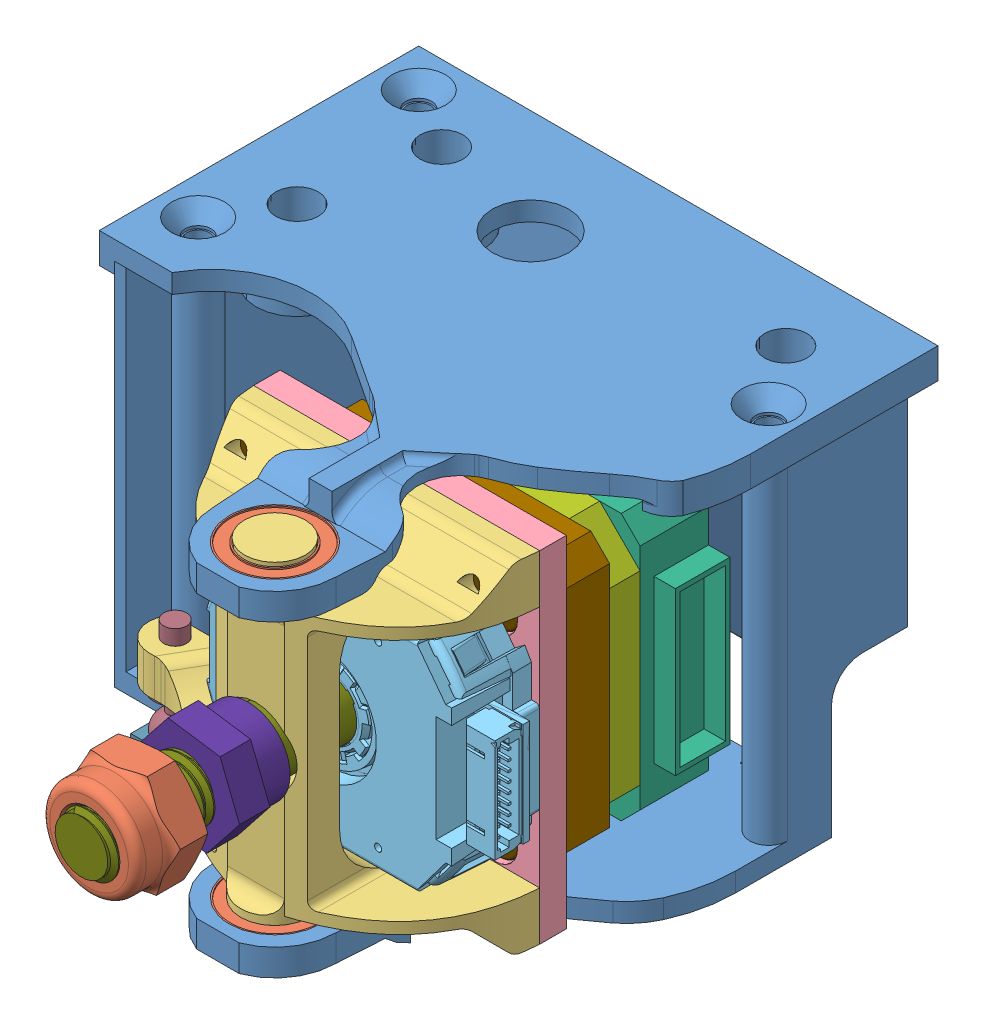
SolidWorks assembly Module Assembly, configuration Default. Lengths in mm.
Overall size (68.25 51.28 97.81).
35 component instances, 21 part files, 49 mates.
Components (placement in the parent):
- Housing-1: Housing [Default] at origin size (64.25 48.5 67.91)
- Bearing 12x8-1: Bearing 12x8 [Default] at (0 -18.25 0.75) x (-0.914388 0 0.40484) z (-0.40484 0 -0.914388) size (12 3.5 12)
- Spindle-1: Spindle [Default] at (0 2 0.75) size (49.04 45 20.5)
- Spindle base-1: Spindle base [Default] at (0 2 -15.25) x (-1 0 0) z (0 -1 0) size (37.62 3.5 44.8)
- Encoder-1: Encoder [Défaut] at (0 2 -12.48) x (0 1 0) z (0 0 1) size (28.68 37.25 10.4)
- Wheel-1: Wheel [Default] at (0 2 -8.55) x (0.929787 0.368098 0) z (0.368098 -0.929787 0) size (81.5 31 81.5) (hidden)
- Stepper Nema14-1: Stepper Nema14 [Predeterminado] at (4.764 -15.5 -30.1157) x (-1 0 0) z (0 1 0) size (37.8 40 35)
  - nema14_base-1: nema14_base [Predeterminado] at (-12.736 -8.6343 35) size (37.8 9 35)
  - nema14_centro-1: nema14_centro [Predeterminado] at (-12.736 0.3657 35) size (35 4 35)
  - nema14_eje-1: nema14_eje [Predeterminado] at (4.764 -6.6343 17.5) x (0 1 0) z (-0.939004 0 0.343907) size (38 5 5)
  - nema14_techo-1: nema14_techo [Predeterminado] at (-12.736 4.3657 35) size (35 9 35)
- Servo motor-1: Servo motor [Default] at (-25.7048 26.288 -66.0832) x (0 0 1) z (1 0 0) size (11.5 29.2 32.5) (flexible)
  - TowerPro-SG90-Body-1: TowerPro-SG90-Body [Default] at (13.6721 7.288 30.7048) size (11.5 26 32.5)
  - ServoFinalGear-1: ServoFinalGear [Default] at (13.6721 33.288 25.7048) x (0.607544 0 -0.794286) z (0.794286 0 0.607544) size (4.64 3.2 4.64)
- Control arm-1: Control arm [Default] at (0 -7.5 -52.4111) x (0.891007 0 0.45399) z (0.45399 0 -0.891007) size (37.9 4.5 7.8)
- Ball joint assy-1: Ball joint assy [Default] at (-26.7302 -5 -12.8697) x (-0.874356 0 0.485286) z (0.485286 0 0.874356) size (15.43 16.21 22.24) (flexible)
  - Ball-1: Ball [Default] at origin size (5.5 15.11 5.5)
  - Joint-1: Joint [Default] at (-3.8823 13.66 -6.9948) x (0.874356 0 -0.485286) z (0 -1 0) size (5.1 22.6 5.1)
- Ball joint assy-2: Ball joint assy [Default] at (-26.7302 -5 -66.0308) x (-0.846813 0 0.531891) z (0.531891 0 0.846813) size (16.34 16.21 21.85) (flexible)
  - Ball-1: Ball [Default] at origin size (5.5 15.11 5.5)
  - Joint-1: Joint [Default] at (4.2551 13.66 6.7745) x (-0.846813 0 0.531891) z (0 -1 0) size (5.1 22.6 5.1)
- Steering rod-1: Steering rod [Default] at (-26.7302 -18.66 -18.4608) x (-0.014502 0.999895 0) z (-0.999895 -0.014502 0) size (3 28.27 3)
- Wheel adapter-1: Wheel adapter [Default] at (0 2 -13.8175) x (0.291296 -0.956633 0) z (-0.956633 -0.291296 0) size (8.34 40 8.37)
- Wheel spacer-1: Wheel spacer [Default] at (0 2 12.25) x (0.368098 -0.929787 0) z (0.929787 0.368098 0) size (13.86 8 12)
- M3x5 din 7984-1: M3x5 din 7984 [Default] at (15.31 20.9 -16.25) x (0.933505 0.358563 0) z (0 0 -1) size (5.5 5.5 7)
- Housing lid-1: Housing lid [Default] at (0 4 0) x (-1 0 0) z (0 0 1) size (68.25 9.28 69.91)
- Bearing 12x8-3: Bearing 12x8 [Default] at (0 22.25 0.75) x (-0.914388 0 0.40484) z (0.40484 0 0.914388) size (12 3.5 12)
- M8 nut-1: M8 nut [Default] at (0 2 16.6825) x (-0.817347 -0.576146 0) z (0 0 1) size (13 16.06 8.5)
- M3x5 din 7984-2: M3x5 din 7984 [Default] at (15.31 -16.9 -16.25) x (-0.933505 0.358563 0) z (0 0 -1) size (5.5 5.5 7)
- M3x5 din 7984-3: M3x5 din 7984 [Default] at (-15.31 20.9 -16.25) x (0.933505 -0.358563 0) z (0 0 -1) size (5.5 5.5 7)
- M3x5 din 7984-4: M3x5 din 7984 [Default] at (-15.31 -16.9 -16.25) x (-0.933505 -0.358563 0) z (0 0 -1) size (5.5 5.5 7)
- M3x5 din 7984-5: M3x5 din 7984 [Default] at (-13 15 -17.75) x (0.999849 0.017374 0) z (0 0 1) size (5.5 5.5 7)
- M3x5 din 7984-6: M3x5 din 7984 [Default] at (-13 -11 -17.75) x (-0.999849 0.017374 0) z (0 0 1) size (5.5 5.5 7)
- M3x5 din 7984-7: M3x5 din 7984 [Default] at (13 15 -17.75) x (0.999849 -0.017374 0) z (0 0 1) size (5.5 5.5 7)
- M3x5 din 7984-8: M3x5 din 7984 [Default] at (13 -11 -17.75) x (-0.999849 -0.017374 0) z (0 0 1) size (5.5 5.5 7)
Mates (geometry in assembly coordinates):
- Concentric1: concentric: cylinder of Housing-1 through (0 -22.5 0.75) axis (0 1 0) radius 6; cylinder of Bearing 12x8-1 through (0 -16.5 0.75) axis (0 -1 0) radius 6
- Coincident1: coincident: plane of Housing-1 through (10 -20 0) normal (0 -1 0); plane of Bearing 12x8-1 through (0 -20 0.75) normal (0 -1 0)
- Concentric2: concentric: cylinder of Bearing 12x8-1 through (0 -16.5 0.75) axis (0 -1 0) radius 4; cylinder of Spindle-1 through (0 -20.5 0.75) axis (0 1 0) radius 4
- Coincident2: coincident: plane of Bearing 12x8-1 through (0 -16.5 0.75) normal (0 1 0); plane of Spindle-1 through (0 -16.5 0.75) normal (0 -1 0)
- Coincident3: coincident: plane of Spindle-1 through (18.81 2 -15.25) normal (0 0 -1); plane of Spindle base-1 through (0 2 -15.25) normal (0 0 1)
- Coincident4: coincident: plane of Spindle-1 through (18.81 24.4 0.75) normal (0 1 0); plane of Spindle base-1 through (18.8109 24.4 -18.75) normal (0 1 0)
- Concentric3: concentric: cylinder of Spindle-1 through (0 2 8.25) axis (0 0 -1) radius 5; cylinder of Encoder-1 through (0 2 -15.25) axis (0 0 -1) radius 6.3
- Coincident6: coincident: plane of Spindle base-1 through (0 2 -15.25) normal (0 0 1); plane of Encoder-1 through (0 2 -15.25) normal (0 0 -1)
- Parallel1: parallel: line of Encoder-1 through (-5.9703 16.2516 -15.25) axis (1 0 0); line of Spindle base-1 through (-18.8109 24.4 -15.25) axis (1 0 0)
- Concentric4: concentric: cylinder of Spindle-1 through (0 2 8.25) axis (0 0 -1) radius 5; cylinder of Wheel-1 through (0 2 -8.55) axis (0 0 1) radius 4
- Distance1: distance = 5 mm: plane of Spindle-1 through (6 -15.5 3.25) normal (0 0 1); plane of Wheel-1 through (0 2 8.25) normal (0 0 -1)
- Coincident10: coincident: plane of Spindle base-1 through (0 2 -18.75) normal (0 0 -1); plane of Stepper Nema14-1/nema14_techo-1 through (17.5 19.5 -18.75) normal (0 0 1)
- Coincident11: coincident: plane of Housing-1 through (0 25 -58.1611) normal (0 0 1); plane of Servo motor-1/TowerPro-SG90-Body-1 through (-6.35 -3.8 -58.1611) normal (0 0 -1)
- Parallel8: parallel: plane of Housing-1 through (10 -21 0) normal (0 1 0); plane of Servo motor-1/TowerPro-SG90-Body-1 through (5 -3.8 -52.4111) normal (0 -1 0)
- Coincident16: coincident: plane of Servo motor-1/ServoFinalGear-1 through (-1.6398 -10.2 -51.034) normal (0 -1 0); plane of Control arm-1 through (0 -10.2 -52.4111) normal (0 1 0)
- Concentric7: concentric: circle of Servo motor-1/ServoFinalGear-1; circle of Control arm-1
- Parallel9: parallel: plane of Control arm-1 through (-1.7706 -12 -48.9362) normal (-0.45399 0 0.891007); line of Spindle-1 through (0 -14 0.75) axis (-0.891007 0 -0.45399)
- Coincident19: coincident: plane of Spindle-1 through (0 -12 5.25) normal (0 -1 0); plane of Control arm-1 through (0 -12 -52.4111) normal (0 -1 0)
- Concentric8: concentric: cylinder of Spindle-1 through (-26.7302 -7 -12.8697) axis (0 -1 0) radius 1.5; cylinder of Ball joint assy-1/Ball-1 through (-26.7302 -5 -12.8697) axis (0 1 0) radius 1.5
- Coincident20: coincident: plane of Spindle-1 through (0 -12 5.25) normal (0 -1 0); plane of Ball joint assy-1/Ball-1 through (-28.0417 -12 -12.1418) normal (0 1 0)
- Coincident25: coincident: plane of Control arm-1 through (0 -12 -52.4111) normal (0 -1 0); plane of Ball joint assy-2/Ball-1 through (-28.0004 -12 -65.233) normal (0 1 0)
- Concentric9: concentric: cylinder of Control arm-1 through (-26.7302 -12 -66.0308) axis (0 1 0) radius 1.6; cylinder of Ball joint assy-2/Ball-1 through (-26.7302 -5 -66.0308) axis (0 1 0) radius 1.5
- Parallel23: parallel: plane of Ball joint assy-2/Joint-1 through (-24.1802 -17.61 -55.9148) normal (0 1 0); plane of Housing-1 through (10 -21 0) normal (0 1 0)
- Coincident35: coincident: plane of Ball joint assy-1/Joint-1 through (-29.2802 -17.61 -22.9857) normal (0 1 0); plane of Ball joint assy-2/Joint-1 through (-24.1802 -17.61 -55.9148) normal (0 1 0)
- Coincident37: coincident: plane of Housing-1 through (0 0 0) normal (1 0 0); plane of Servo motor-1/TowerPro-SG90-Body-1 through (0 19 -52.4111) normal (-1 0 0)
- Concentric15: concentric: cylinder of Spindle base-1 through (-13 -11 -18.75) axis (0 0 1) radius 1.5; cylinder of Stepper Nema14-1/nema14_techo-1 through (-13 -11 -25.75) axis (0 0 1) radius 1.5
- Concentric16: concentric: cylinder of Spindle base-1 through (13 15 -18.75) axis (0 0 1) radius 1.5; cylinder of Stepper Nema14-1/nema14_techo-1 through (13 15 -25.75) axis (0 0 1) radius 1.5
- Concentric20: concentric: cylinder of Stepper Nema14-1/nema14_eje-1 through (0 2 -36.75) axis (0 0 -1) radius 2.5; cylinder of Wheel adapter-1 through (0 2 -13.8175) axis (0 0 -1) radius 2.5
- Coincident42: coincident: plane of Encoder-1 through (0 2 -13.8175) normal (0 0 -1); plane of Wheel adapter-1 through (0.7282 -0.3916 -13.8175) normal (0 0 -1)
- Concentric21: concentric: cylinder of Wheel spacer-1 through (0 2 4.25) axis (0 0 1) radius 3.45; cylinder of Wheel adapter-1 through (0 2 -13.8175) axis (0 0 -1) radius 4
- Coincident43: coincident: plane of Wheel-1 through (0 2 12.25) normal (0 0 -1); plane of Wheel spacer-1 through (0 2 12.25) normal (0 0 1)
- Coincident44: coincident: plane of Wheel spacer-1 through (4.3036 7.4295 4.25) normal (0.929787 0.368098 0); line of Wheel-1 through (4.3036 7.4295 8.25) axis (0.368098 -0.929787 0)
- Parallel29: parallel: line of Spindle base-1 through (18.8109 24.4 -18.75) axis (0 -1 0); line of Spindle-1 through (18.81 -20.4 -15.25) axis (0 1 0)
- Coincident45: coincident: plane of Spindle base-1 through (0 2 -16.25) normal (0 0 -1); plane of M3x5 din 7984-1 through (16.296 18.3329 -16.25) normal (0 0 1)
- Concentric22: concentric: cylinder of Spindle base-1 through (15.31 20.9 -18.75) axis (0 0 1) radius 1.6; cylinder of M3x5 din 7984-1 through (15.31 20.9 -18.25) axis (0 0 -1) radius 1.5
- Concentric23: concentric: cylinder of Spindle-1 through (-15.31 20.9 -9.25) axis (0 0 -1) radius 1.5; cylinder of Spindle base-1 through (-15.31 20.9 -18.75) axis (0 0 1) radius 1.6
- Coincident46: coincident: plane of Spindle-1 through (0 20.5 0.75) normal (0 1 0); plane of Housing lid-1 through (0 20.5 0) normal (0 -1 0)
- Concentric24: concentric: cylinder of Spindle-1 through (0 24.5 0.75) axis (0 -1 0) radius 4; cylinder of Housing lid-1 through (0 26.5 0.75) axis (0 -1 0) radius 6
- Concentric26: concentric: circle of Ball joint assy-2/Joint-1; circle of Steering rod-1
- Coincident54: coincident: plane of Ball joint assy-2/Joint-1 through (-29.2802 -16.11 -46.7308) normal (0 0 1); plane of Steering rod-1 through (-26.7302 -18.66 -46.7308) normal (0 0 -1)
- Parallel37: parallel: plane of Ball joint assy-1/Joint-1 through (-24.1802 -16.11 -32.1697) normal (0 0 -1); plane of Steering rod-1 through (-26.7302 -18.66 -18.4608) normal (0 0 1)
- Parallel38: parallel: cylinder of Ball joint assy-1/Joint-1 through (-26.7302 -18.66 -14.0635) axis (0 0 -1) radius 2.55; cylinder of Ball joint assy-2/Joint-1 through (-26.7302 -18.66 -64.8371) axis (0 0 1) radius 2.55
- Concentric30: concentric: circle of Ball joint assy-1/Joint-1; circle of Steering rod-1
- Coincident55: coincident: plane of Housing-1 through (-41.5 0 0) normal (-1 0 0); plane of Housing lid-1 through (-41.5 23.5 -59.6611) normal (1 0 0)
- Angle1: planar angle = 0 rad: plane of Housing-1 through (0 0 0) normal (0 0 1); plane of Spindle-1 through (0 2 0.75) normal (0 0 1)
- Concentric31: concentric: circle of Wheel adapter-1; cylinder of M8 nut-1 through (0 2 16.6825) axis (0 0 -1) radius 3.3234
- Distance2: distance = 1 mm: plane of Wheel adapter-1 through (0 2 26.1825) normal (0 0 1); plane of M8 nut-1 through (-3.15 -4.8131 25.1825) normal (0 0 1)
- Coincident56: coincident: circle of Spindle base-1; cylinder of M3x5 din 7984-5 through (-13 15 -15.75) axis (0 0 1) radius 1.5
- Coincident57: coincident: plane of Spindle base-1 through (-13 15 -17.75) normal (0 0 1); circle of M3x5 din 7984-5
